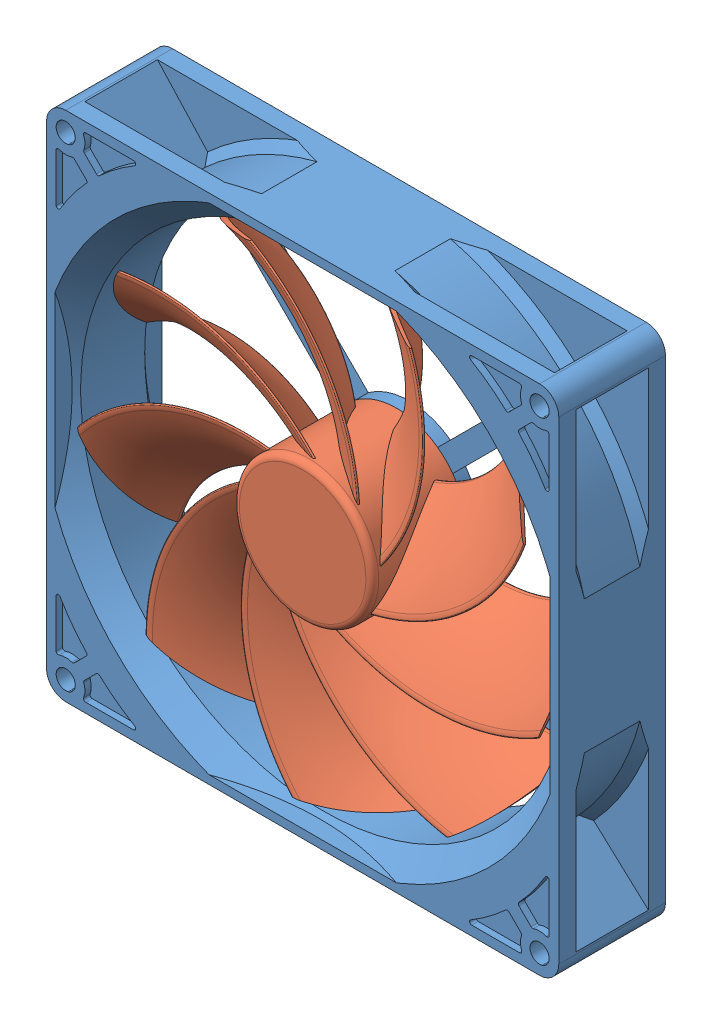
SolidWorks assembly PC FAN, configuration Default. Lengths in mm.
Overall size (183.81 183.8 33.39).
2 component instances, 2 part files, 2 mates.
Components (placement in the parent):
- CPU Fan with no fan-1: CPU Fan with no fan [Default] at origin size (120 120 33.39)
- Part3^PC FAN-1: Part3^PC FAN [Default] at (0 0 -9.5) x (-0.828072 -0.560621 0) z (0 0 1) size (132.38 132.34 22) (virtual)
Mates (geometry in assembly coordinates):
- Coincident5: coincident anti-aligned: plane of CPU Fan with no fan-1 through (0 0 -9.5) normal (0 0 1); plane of Part3^PC FAN-1 through (0 0 -9.5) normal (0 0 -1)
- Concentric1: concentric aligned: cylinder of CPU Fan with no fan-1 through (0 0 -9.5) axis (0 0 -1) radius 16.3; cylinder of Part3^PC FAN-1 through (0 0 12.5) axis (0 0 -1) radius 16.3
